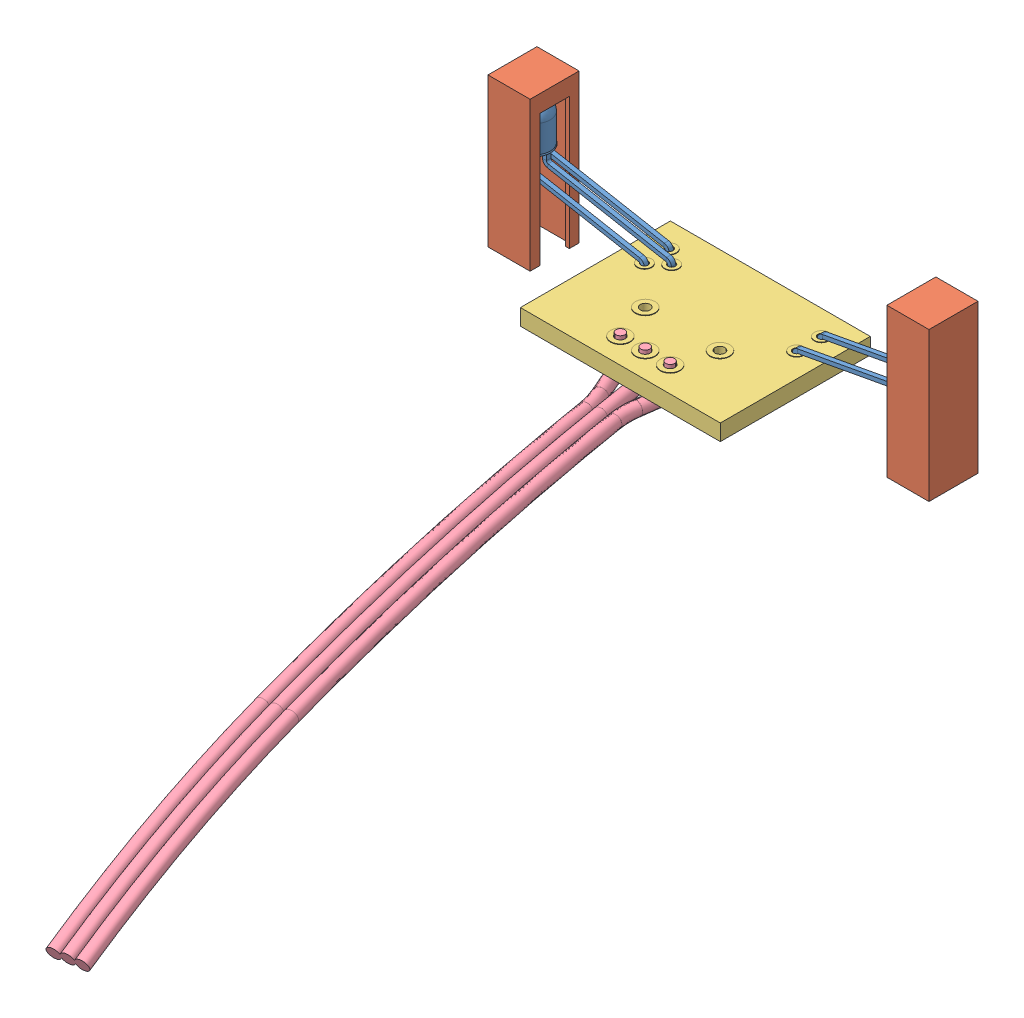
SolidWorks assembly preferenceV2_dispenser_IRAssembly, configuration Default. Lengths in mm.
Overall size (45 23.68 83.96).
8 component instances, 4 part files, 10 mates.
Components (placement in the parent):
- sparkfunIR_LEDandCase-1: sparkfunIR_LEDandCase [2Pin] at (-20.5025 21.2786 44.4241) x (-1 0 0) z (0 0 -1) size (14.94 15.2 5)
  - sparkfunIR_LED-1: sparkfunIR_LED [2Pin] at (-40.5025 -12.0786 32.4491) size (14.24 9.86 3.2)
  - sparkfunIR_casing-1: sparkfunIR_casing [Default] at (-40.6525 -5.8286 32.4491) x (1 0 0) z (0 0 -1) size (4.3 15.2 5)
- sparkfunIR_LEDandCase-2: sparkfunIR_LEDandCase [3Pin] at (20.1025 21.2786 -20.474) x (1 0 0.000001) z (-0.000001 0 1) size (16.44 15.2 5)
  - sparkfunIR_LED-1: sparkfunIR_LED [3Pin] at (-40.5025 -12.0786 32.4491) size (15.74 9.86 3.2)
  - sparkfunIR_casing-1: sparkfunIR_casing [Default] at (-40.6525 -5.8286 32.4491) x (1 0 0) z (0 0 -1) size (4.3 15.2 5)
- sparkfunIR_breakoutBoard-1: sparkfunIR_breakoutBoard [Default] at (-0.2 4.7137 15.815) x (-1 0 0) z (0 0 -1) size (20.4 1.75 15.3)
- dispenser_wires-1: dispenser_wires [Default] at origin size (16.82 14.15 71.86)
Mates (geometry in assembly coordinates):
- Coincident75: coincident: plane of sparkfunIR_breakoutBoard-1 through (-0.2 4.7137 10.705) normal (0 0 -1); moEndPointRef_w of sparkfunIR_LEDandCase-1/sparkfunIR_LED-1
- Parallel8: parallel aligned: plane of sparkfunIR_breakoutBoard-1 through (-0.2 3.8887 15.815) normal (0 -1 0); plane of sparkfunIR_LEDandCase-1/sparkfunIR_LED-1 through (7.56 3.8387 11.975) normal (0 -1 0)
- Coincident76: coincident: plane of sparkfunIR_breakoutBoard-1 through (-0.2 4.7137 10.705) normal (0 0 -1); unknown of sparkfunIR_LEDandCase-2/sparkfunIR_LED-1
- Concentric3: concentric anti-aligned: cylinder of sparkfunIR_breakoutBoard-1 through (-2.74 5.5387 20.925) axis (0 -1 0) radius 0.5; cylinder of Copy of Wires^irAssembly_preferenceV2_dispenserAssembly-1 through (-2.74 3.6347 20.925) axis (0 1 0) radius 0.45
- Concentric4: concentric anti-aligned: cylinder of sparkfunIR_breakoutBoard-1 through (2.34 5.5387 20.925) axis (0 -1 0) radius 0.5; cylinder of Copy of Wires^irAssembly_preferenceV2_dispenserAssembly-1 through (2.34 3.6347 20.925) axis (0 1 0) radius 0.45
- Coincident90: coincident anti-aligned: plane of sparkfunIR_breakoutBoard-1 through (-2.74 3.8387 20.925) normal (0 -1 0); plane of Copy of Wires^irAssembly_preferenceV2_dispenserAssembly-1 through (-2.74 3.8387 20.925) normal (0 1 0)
- Coincident92: coincident: point of sparkfunIR_LEDandCase-1/sparkfunIR_LED-1; point of sparkfunIR_breakoutBoard-1
- Coincident93: coincident: point of sparkfunIR_LEDandCase-2/sparkfunIR_LED-1; point of sparkfunIR_breakoutBoard-1
- Coincident94: coincident: point of sparkfunIR_LEDandCase-2/sparkfunIR_LED-1; point of sparkfunIR_breakoutBoard-1
- Coincident96: coincident: point of sparkfunIR_LEDandCase-2/sparkfunIR_LED-1; point of sparkfunIR_breakoutBoard-1
